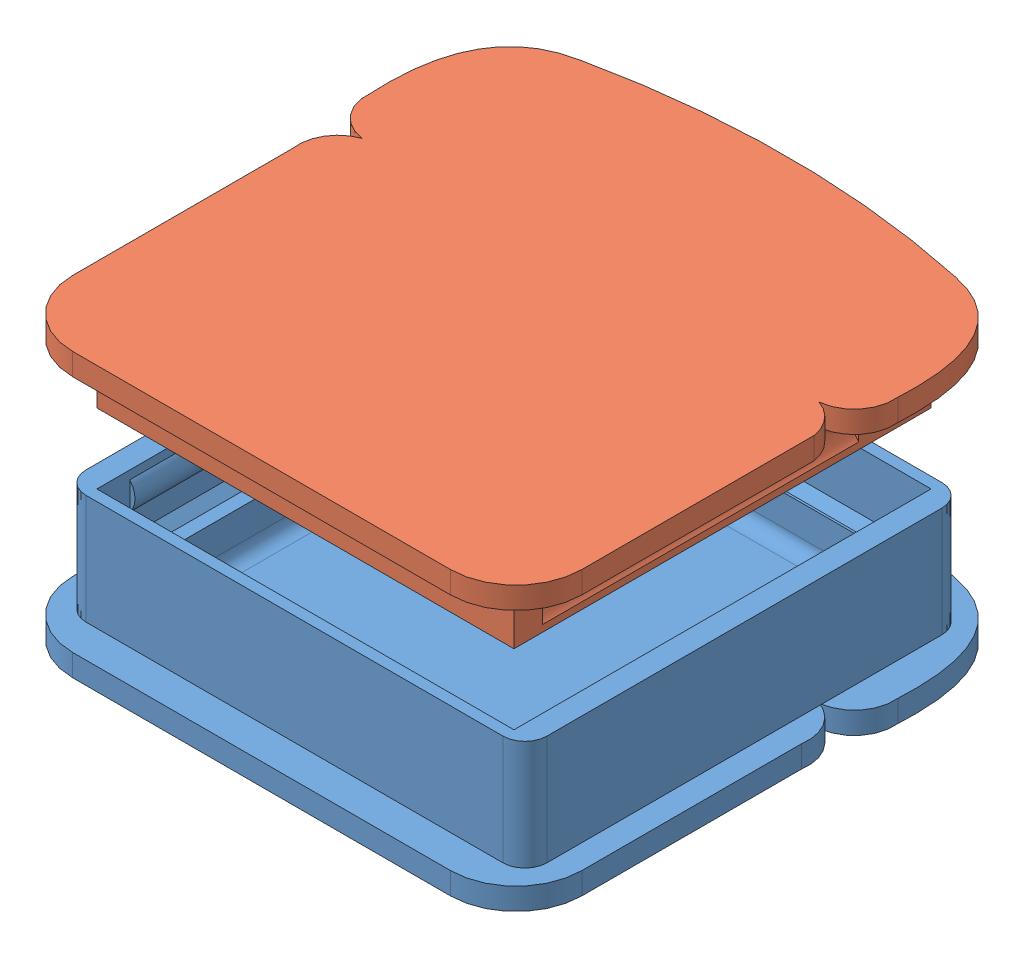
SolidWorks assembly Assembly of PBJ Box, configuration Default. Lengths in mm.
Overall size (154.23 81.76 152.14).
2 component instances, 2 part files, 2 mates.
Components (placement in the parent):
- PBJ Box Bottom-1: PBJ Box Bottom [Default] at (-45.1535 -4.2612 26.7219) size (154.23 38.1 152.14)
- PBJ Box Top-1: PBJ Box Top [Default] at (-45.1535 77.497 26.7219) x (-1 0 0) z (0 0 1) size (154.23 25.91 152.14)
Mates (geometry in assembly coordinates):
- Coincident4: coincident anti-aligned: plane of PBJ Box Bottom-1 through (-105.4785 33.8388 -33.6031) normal (1 0 0); plane of PBJ Box Top-1 through (-105.4785 51.589 -33.6031) normal (-1 0 0)
- Coincident5: coincident anti-aligned: plane of PBJ Box Bottom-1 through (-105.4785 33.8388 87.0469) normal (0 0 -1); plane of PBJ Box Top-1 through (15.1715 51.589 87.0469) normal (0 0 1)
